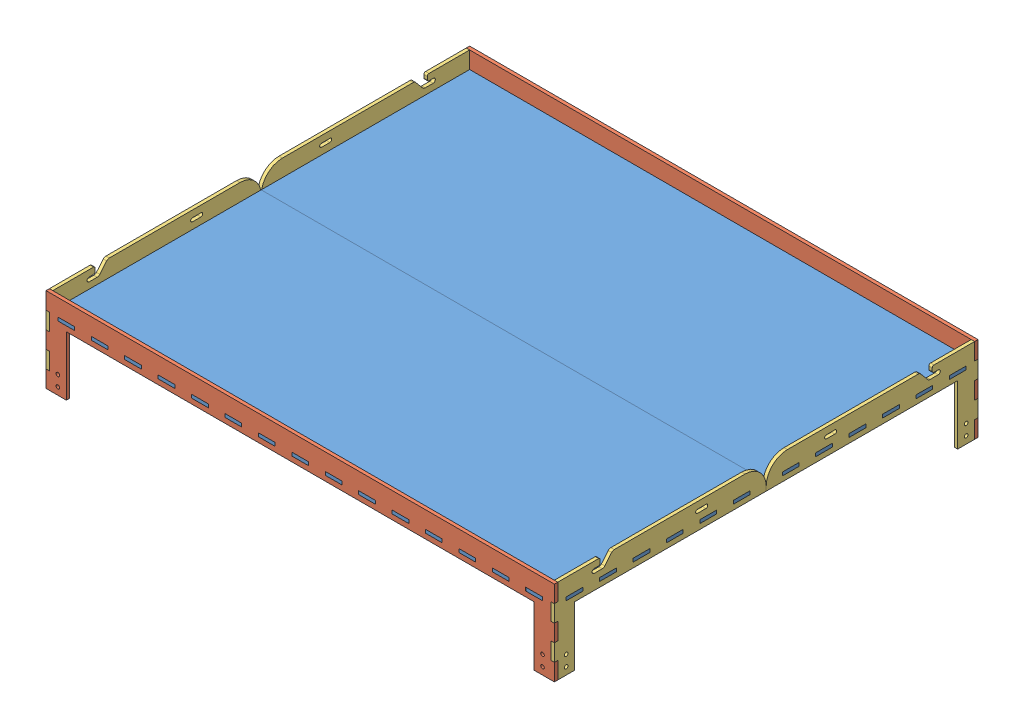
SolidWorks assembly workspace, configuration Default. Lengths in mm.
Overall size (600.02 100 500).
8 component instances, 3 part files, 21 mates.
Components (placement in the parent):
- basepanel-1: basepanel [Default] at origin size (600.02 4 250)
- rearpanel-1: rearpanel [Default] at (0.0125 0 -250) x (1 0 0) z (0 -1 0) size (600 4 100)
- sidepanel-2: sidepanel [Default] at (300.0125 -76 -250) x (0 0 1) z (0 -1 0) size (250 4 100)
- sidepanel-3: sidepanel [Default] at (-296.0125 -76 -250) x (0 0 1) z (0 -1 0) size (250 4 100)
- basepanel-2: basepanel [Default] x (-1 0 0) z (0 0 -1) size (600.02 4 250)
- sidepanel-6: sidepanel [Default] at (296.0125 -76 250) x (0 0 -1) z (0 -1 0) size (250 4 100)
- rearpanel-3: rearpanel [Default] at (0.0125 0 250) x (-1 0 0) z (0 -1 0) size (600 4 100)
- sidepanel-7: sidepanel [Default] at (-300.0125 -76 250) x (0 0 -1) z (0 -1 0) size (250 4 100)
Mates (geometry in assembly coordinates):
- Coincident1: coincident: plane of basepanel-1 through (0 4 0) normal (0 1 0); plane of rearpanel-1 through (285.845 4 -246) normal (0 -1 0)
- Coincident2: coincident: plane of basepanel-1 through (266.2875 4 -250) normal (0 0 -1); plane of rearpanel-1 through (0.0125 0 -250) normal (0 0 -1)
- Coincident3: coincident: plane of basepanel-1 through (296.0125 4 -246) normal (1 0 0); plane of rearpanel-1 through (296.0125 -36 -246) normal (1 0 0)
- Coincident4: coincident: plane of basepanel-1 through (0 4 0) normal (0 1 0); plane of sidepanel-2 through (296.0125 4 -38.75) normal (0 -1 0)
- Coincident5: coincident: plane of basepanel-1 through (300.0125 4 -38.75) normal (1 0 0); plane of sidepanel-2 through (300.0125 -1 -25) normal (1 0 0)
- Coincident6: coincident: plane of rearpanel-1 through (0.0125 0 -250) normal (0 0 -1); plane of sidepanel-2 through (296.0125 -16 -250) normal (0 0 -1)
- Coincident7: coincident: plane of basepanel-1 through (0 4 0) normal (0 1 0); plane of sidepanel-3 through (-300.0125 4 -236) normal (0 -1 0)
- Coincident9: coincident: plane of basepanel-1 through (-300.0125 4 -38.75) normal (-1 0 0); plane of sidepanel-3 through (-300.0125 -1 -25) normal (-1 0 0)
- Coincident10: coincident: plane of sidepanel-3 through (-300.0125 -16 -250) normal (0 0 -1); plane of rearpanel-1 through (0.0125 0 -250) normal (0 0 -1)
- Coincident11: coincident: plane of basepanel-1 through (0 4 0) normal (0 1 0); plane of basepanel-2 through (0 4 0) normal (0 1 0)
- Coincident12: coincident: plane of basepanel-1 through (-296.0125 4 0) normal (-1 0 0); plane of basepanel-2 through (-296.0125 4 99.025) normal (-1 0 0)
- Coincident13: coincident: plane of basepanel-1 through (100 4 -25) normal (0 0 1); plane of basepanel-2 through (-100 4 -25) normal (0 0 -1)
- Coincident14: coincident: plane of basepanel-2 through (0 4 0) normal (0 1 0); plane of ? through (-285.845 4 330) normal (0 -1 0)
- Coincident15: coincident: plane of basepanel-2 through (-266.2875 4 330) normal (0 0 1); plane of ? through (-0.0125 0 330) normal (0 0 1)
- Coincident16: coincident: plane of basepanel-2 through (-296.0125 4 326) normal (-1 0 0); plane of ? through (-296.0125 24 330) normal (-1 0 0)
- Coincident17: coincident: plane of basepanel-2 through (0 4 0) normal (0 1 0); plane of ? through (300.0125 4 316) normal (0 -1 0)
- Coincident18: coincident: plane of ? through (-0.0125 0 330) normal (0 0 1); plane of ? through (300.0125 4 330) normal (0 0 1)
- Coincident19: coincident: plane of basepanel-2 through (300.0125 4 276.55) normal (1 0 0); plane of ? through (300.0125 11.5 32.5) normal (1 0 0)
- Coincident20: coincident: plane of basepanel-2 through (0 4 0) normal (0 1 0); plane of ? through (-296.0125 4 316) normal (0 -1 0)
- Coincident21: coincident: plane of basepanel-2 through (-300.0125 4 316) normal (-1 0 0); plane of ? through (-300.0125 11.5 32.5) normal (-1 0 0)
- Coincident22: coincident: plane of ? through (-0.0125 0 330) normal (0 0 1); plane of ? through (-296.0125 4 330) normal (0 0 1)
